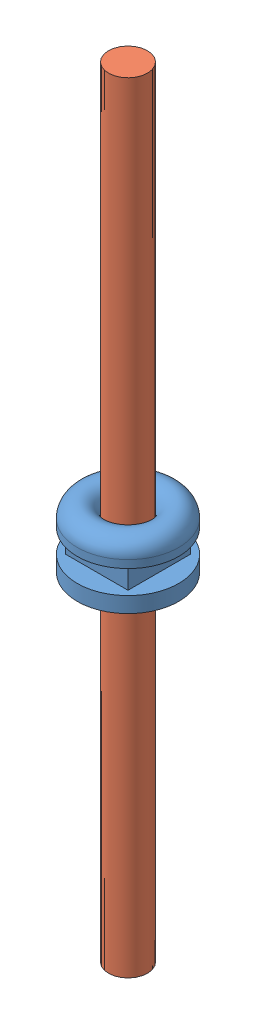
SolidWorks assembly Cable, configuration Default. Lengths in mm.
Overall size (18.42 100 14.33).
2 component instances, 2 part files, 1 mates.
Components (placement in the parent):
- cableReliefClamp-2: cableReliefClamp [По умолчанию] at origin size (18.42 8 14.33)
- cable-1: cable [По умолчанию] at (0 -48.3057 0) x (0.850759 0 -0.525556) z (0 1 0) size (5 5 100)
Mates (geometry in assembly coordinates):
- Concentric1: concentric anti-aligned: cylinder of cableReliefClamp-2 through (0 0 0) axis (0 1 0) radius 2.5; cylinder of cable-1 through (0 51.6943 0) axis (0 -1 0) radius 2.5
